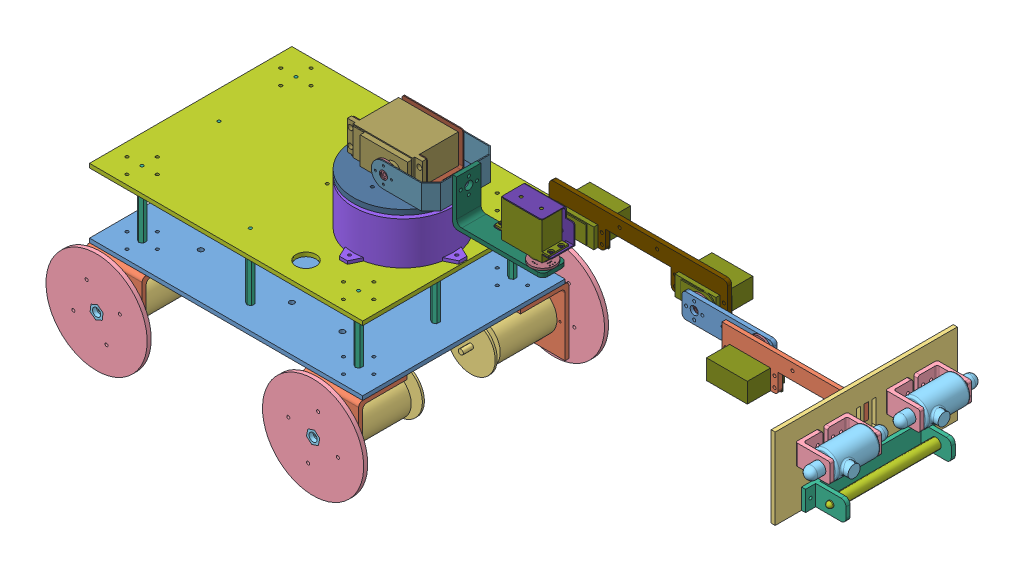
SolidWorks assembly robot_config4, configuration Default. Lengths in mm.
Overall size (760.42 282.73 242).
55 component instances, 25 part files, 137 mates.
Components (placement in the parent):
- base_odroid_down_fix-1: base_odroid_down_fix [Default] at (39.4639 122.941 229.7749) x (1 0 0) z (0 -1 0) size (270 200 4)
- link_motor_1_port-1: link_motor_1_port [Default] at (221.3654 112.3394 287.3354) x (0 0 -1) z (1 0 0) size (48 66 56)
- motor_dc_NISCA-1: motor_dc_NISCA [Default] at (244.2642 39.7289 313.6416) x (0 -1 0) z (0 0 -1) size (54 48 92)
- roda_shaft-1: roda_shaft [Default] at (185.8398 121.6563 330.6416) x (-0.980223 0.197896 0) z (0 0 1) size (100 100 4)
- shaft_adapter_5mm-1: shaft_adapter_5mm [Default] at (248.7954 72.9583 317.6416) x (0.980223 -0.197896 0) z (0 0 1) size (12 13.86 17)
- link_motor_1_port-2: link_motor_1_port [Default] at (221.3654 112.3394 139.9479) x (0 0 1) z (-1 0 0) size (48 66 56)
- motor_dc_NISCA-2: motor_dc_NISCA [Default] at (198.4666 39.7289 113.6416) x (0 -1 0) z (0 0 1) size (54 48 92)
- shaft_adapter_5mm-3: shaft_adapter_5mm [Default] at (238.0112 59.5291 109.6416) x (0.404857 -0.91438 0) z (0 0 -1) size (12 13.86 17)
- roda_shaft-2: roda_shaft [Default] at (222.1063 135.748 96.6416) x (0.589448 0.807807 0) z (0 0 -1) size (100 100 4)
- link_motor_1_port-5: link_motor_1_port [Default] at (7.3654 112.3394 287.3354) x (0 0 -1) z (1 0 0) size (48 66 56)
- motor_dc_NISCA-5: motor_dc_NISCA [Default] at (-15.5334 128.1531 313.6416) x (0 1 0) z (0 0 -1) size (54 48 92)
- roda_shaft-5: roda_shaft [Default] at (51.5287 56.8466 334.6416) x (0.393495 -0.919327 0) z (0 0 -1) size (100 100 4)
- shaft_adapter_5mm-6: shaft_adapter_5mm [Default] at (0.8367 112.7577 317.6416) x (-0.393495 0.919327 0) z (0 0 1) size (12 13.86 17)
- link_motor_1_port-6: link_motor_1_port [Default] at (7.3654 112.3394 139.9479) x (0 0 1) z (-1 0 0) size (48 66 56)
- motor_dc_NISCA-6: motor_dc_NISCA [Default] at (-15.5334 39.7289 113.6416) x (0 -1 0) z (0 0 1) size (54 48 92)
- roda_shaft-6: roda_shaft [Default] at (45.258 48.6046 96.6416) x (0.202799 -0.97922 0) z (0 0 -1) size (100 100 4)
- shaft_adapter_5mm-7: shaft_adapter_5mm [Default] at (36.6325 79.8838 109.6416) x (0.949429 -0.313981 0) z (0 0 -1) size (12 13.86 17)
- spacer_6cm-2: spacer_6cm [Default] at (221.7099 182.941 288.7798) x (0.5 0 -0.866025) z (0 -1 0) size (6 6.93 68)
- spacer_6cm-3: spacer_6cm [Default] at (114.7099 182.941 288.7798) x (0.5 0 -0.866025) z (0 -1 0) size (6 6.93 68)
- spacer_6cm-4: spacer_6cm [Default] at (7.7099 182.941 288.7798) x (0.5 0 -0.866025) z (0 -1 0) size (6 6.93 68)
- spacer_6cm-5: spacer_6cm [Default] at (221.7099 182.941 212.7798) x (0.5 0 -0.866025) z (0 -1 0) size (6 6.93 68)
- spacer_6cm-7: spacer_6cm [Default] at (7.7099 182.941 212.7798) x (0.5 0 -0.866025) z (0 -1 0) size (6 6.93 68)
- spacer_6cm-8: spacer_6cm [Default] at (221.7099 182.941 136.7798) x (0.5 0 -0.866025) z (0 -1 0) size (6 6.93 68)
- spacer_6cm-9: spacer_6cm [Default] at (114.7099 182.941 136.7798) x (0.5 0 -0.866025) z (0 -1 0) size (6 6.93 68)
- spacer_6cm-10: spacer_6cm [Default] at (7.7099 182.941 136.7798) x (0.5 0 -0.866025) z (0 -1 0) size (6 6.93 68)
- base_odroid_up_fix-1: base_odroid_up_fix [Default] at (189.2669 186.941 197.5083) x (-1 0 0) z (0 -1 0) size (270 200 4)
- base_arm-1: base_arm [Default] at (189.3654 194.0898 219.4289) x (0 0 1) z (-1 0 0) size (118.01 42 118.01)
- servo_hs422-1: servo_hs422 [Default] at (199.6524 210.6756 203.7356) x (0 0 1) z (-1 0 0) size (19.81 42.14 58.23)
- link1_arm-1: link1_arm [Default] at (162.7148 232.0663 213.6416) x (-1 0 0) z (0 1 0) size (98 98 12)
- bracket_servo_hs755-1: bracket_servo_hs755 [Default] at (226.3654 266.4802 252.854) x (0 0 1) z (-1 0 0) size (44 34 74)
- servo_hs755-1: servo_hs755 [Default] at (199.4663 211.9363 188.6416) x (0 -1 0) z (0 0 1) size (29 74 56.99)
- servo_horn_general-1: servo_horn_general [Default] at (158.1724 253.8913 247.6316) x (-1 0 0) z (0 0 -1) size (24 24 6)
- link2_ubracket-2: link2_ubracket [Default] at (243.847 269.0663 202.3382) x (0 0 -1) z (0 -1 0) size (66 59 24)
- link2_fix-2: link2_fix [Default] at (302.1273 265.014 203.2174) x (0 1 0) z (0 0 1) size (45.14 89 24)
- servo_horn_general-2: servo_horn_general [Default] at (282.1724 229.0663 212.0424) x (-1 0 0) z (0 1 0) size (24 24 6)
- servo_hs645-2: servo_hs645 [Default] at (371.772 273.4208 228.4385) x (1 0 0) z (0 -1 0) size (53.34 19.56 42.35)
- bracket_servo_645-2: bracket_servo_645 [Default] at (346.6974 227.1529 209.3754) x (0 -1 0) z (-1 0 0) size (34 24 57)
- servo_horn_general-3: servo_horn_general [Default] at (280.7737 260.864 201.2504) x (-0.965926 0.258819 0) z (0 0 -1) size (24 24 6)
- servo_hs645-3: servo_hs645 [Default] at (283.7908 238.6247 156.8959) x (-1 0 0) z (0 0 1) size (53.34 19.56 42.35)
- link4_fix-1: link4_fix [Default] at (524.8795 244.4473 185.4709) size (176.25 35 4)
- servo_hs645-4: servo_hs645 [Default] at (511.566 264.5589 156.8959) size (53.34 19.56 42.35)
- link5_fix-1: link5_fix [Default] at (491.6097 296.6345 201.2504) x (0 1 0) z (0 0 1) size (24 90 4)
- servo_horn_general-4: servo_horn_general [Default] at (421.9664 248.1628 201.2504) x (-1 0 0) z (0 0 -1) size (24 24 6)
- servo_horn_general-5: servo_horn_general [Default] at (581.3523 248.1628 205.2504) size (24 24 6)
- servo_hs645-5: servo_hs645 [Default] at (491.7528 264.5589 249.6049) x (-1 0 0) z (0 0 -1) size (53.34 19.56 42.35)
- link6_eff-1: link6_eff [Default] at (498.4393 244.4473 226.6809) x (-1 0 0) z (0 0 -1) size (140.63 35 4)
- base_link_effector_fix-2: base_link_effector_fix [Default] at (654.1404 277.9299 227.3815) x (0 0 -1) z (1 0 0) size (180 80 4)
- base_webcam_fix1-2: base_webcam_fix1 [Default] at (658.1404 278.3128 294.6809) x (0 0 -1) z (0 -1 0) size (23 34 20)
- base_webcam_fix1-3: base_webcam_fix1 [Default] at (658.1404 258.3128 243.6809) x (0 0 1) z (0 1 0) size (23 34 20)
- base_webcam_fix1-4: base_webcam_fix1 [Default] at (658.1404 278.3128 205.6809) x (0 0 -1) z (0 -1 0) size (23 34 20)
- base_webcam_fix1-5: base_webcam_fix1 [Default] at (658.1404 258.3128 154.6809) x (0 0 1) z (0 1 0) size (23 34 20)
- webcam_sturdy-3: webcam_sturdy [Default] at (682.1404 268.3128 243.37) x (0 0 -1) z (1 0 0) size (79 27 33.5)
- webcam_sturdy-4: webcam_sturdy [Default] at (682.1404 268.3128 154.37) x (0 0 -1) z (1 0 0) size (79 27 33.5)
- base_GM-1: base_GM [Default] at (666.3876 236.8128 184.9491) x (0 0 -1) z (0 -1 0) size (128 34 20)
- tabung_GM-1: tabung_GM [Default] at (725.7289 219.2089 174.6809) x (0.998525 0.054289 0) z (0 0 1) size (10 10 116)
Mates (geometry in assembly coordinates):
- Coincident1: coincident anti-aligned: plane of link_motor_1_port-1 through (193.3654 52.941 313.6416) normal (0 0 -1); plane of motor_dc_NISCA-1 through (221.3654 83.941 313.6416) normal (0 0 1)
- Concentric1: concentric aligned: cylinder of link_motor_1_port-1 through (221.3654 83.941 317.6416) axis (0 0 -1) radius 9.5; cylinder of motor_dc_NISCA-1 through (221.3654 83.941 317.6416) axis (0 0 -1) radius 9
- Concentric2: concentric anti-aligned: cylinder of link_motor_1_port-1 through (221.3654 106.941 317.6416) axis (0 0 -1) radius 1; cylinder of motor_dc_NISCA-1 through (221.3654 106.941 311.6416) axis (0 0 1) radius 1.5
- Coincident2: coincident anti-aligned: plane of motor_dc_NISCA-1 through (244.2642 39.7289 317.6416) normal (0 0 1); plane of shaft_adapter_5mm-1 through (221.3654 83.941 317.6416) normal (0 0 -1)
- Concentric4: concentric aligned: cylinder of motor_dc_NISCA-1 through (221.3654 83.941 330.6416) axis (0 0 -1) radius 2.5; cylinder of shaft_adapter_5mm-1 through (221.3654 83.941 330.6416) axis (0 0 -1) radius 2.5
- Coincident3: coincident anti-aligned: plane of roda_shaft-1 through (222.7365 90.7322 330.6416) normal (0.318728 -0.947846 0); plane of shaft_adapter_5mm-1 through (222.7365 90.7322 334.6416) normal (-0.318728 0.947846 0)
- Coincident4: coincident aligned: plane of roda_shaft-1 through (221.3654 83.941 334.6416) normal (0 0 1); plane of shaft_adapter_5mm-1 through (248.7954 72.9583 334.6416) normal (0 0 1)
- Coincident7: coincident anti-aligned: plane of roda_shaft-1 through (214.7985 81.7328 330.6416) normal (0.661495 0.74995 0); plane of shaft_adapter_5mm-1 through (214.7985 81.7328 334.6416) normal (-0.661495 -0.74995 0)
- Coincident8: coincident anti-aligned: plane of link_motor_1_port-2 through (249.3654 52.941 113.6416) normal (0 0 1); plane of motor_dc_NISCA-2 through (221.3654 83.941 113.6416) normal (0 0 -1)
- Concentric5: concentric aligned: cylinder of link_motor_1_port-2 through (221.3654 83.941 109.6416) axis (0 0 1) radius 9.5; cylinder of motor_dc_NISCA-2 through (221.3654 83.941 109.6416) axis (0 0 1) radius 9
- Concentric7: concentric anti-aligned: cylinder of link_motor_1_port-2 through (221.3654 106.941 109.6416) axis (0 0 1) radius 1; cylinder of motor_dc_NISCA-2 through (221.3654 106.941 115.6416) axis (0 0 -1) radius 1.5
- Coincident9: coincident anti-aligned: plane of base_odroid_down_fix-1 through (39.4639 118.941 229.7749) normal (0 -1 0); plane of link_motor_1_port-1 through (193.3654 118.941 269.6416) normal (0 1 0)
- Concentric8: concentric anti-aligned: cylinder of base_odroid_down_fix-1 through (206.3654 118.941 289.6416) axis (0 1 0) radius 1.5; cylinder of link_motor_1_port-1 through (206.3654 118.941 289.6416) axis (0 -1 0) radius 1.5
- Concentric9: concentric anti-aligned: cylinder of base_odroid_down_fix-1 through (236.3654 118.941 289.6416) axis (0 1 0) radius 1.5; cylinder of link_motor_1_port-1 through (236.3654 118.941 289.6416) axis (0 -1 0) radius 1.5
- Coincident11: coincident aligned: plane of shaft_adapter_5mm-3 through (238.0112 59.5291 92.6416) normal (0 0 -1); plane of roda_shaft-2 through (221.3654 83.941 92.6416) normal (0 0 -1)
- Coincident12: coincident anti-aligned: plane of shaft_adapter_5mm-3 through (220.627 77.0523 92.6416) normal (-0.589448 -0.807807 0); plane of roda_shaft-2 through (220.627 77.0523 96.6416) normal (0.589448 0.807807 0)
- Coincident13: coincident anti-aligned: plane of shaft_adapter_5mm-3 through (227.7004 86.746 92.6416) normal (0.994305 -0.106573 0); plane of roda_shaft-2 through (227.7004 86.746 96.6416) normal (-0.994305 0.106573 0)
- Coincident14: coincident anti-aligned: plane of motor_dc_NISCA-2 through (198.4666 39.7289 109.6416) normal (0 0 -1); plane of shaft_adapter_5mm-3 through (221.3654 83.941 109.6416) normal (0 0 1)
- Concentric10: concentric aligned: cylinder of motor_dc_NISCA-2 through (221.3654 83.941 96.6416) axis (0 0 1) radius 2.5; cylinder of shaft_adapter_5mm-3 through (221.3654 83.941 96.6416) axis (0 0 1) radius 2.5
- Coincident15: coincident anti-aligned: plane of base_odroid_down_fix-1 through (39.4639 118.941 229.7749) normal (0 -1 0); plane of link_motor_1_port-2 through (249.3654 118.941 157.6416) normal (0 1 0)
- Concentric11: concentric anti-aligned: cylinder of base_odroid_down_fix-1 through (206.3654 118.941 137.6416) axis (0 1 0) radius 1.5; cylinder of link_motor_1_port-2 through (206.3654 118.941 137.6416) axis (0 -1 0) radius 1.5
- Concentric12: concentric anti-aligned: cylinder of base_odroid_down_fix-1 through (236.3654 118.941 137.6416) axis (0 1 0) radius 1.5; cylinder of link_motor_1_port-2 through (236.3654 118.941 137.6416) axis (0 -1 0) radius 1.5
- Coincident16: coincident anti-aligned: plane of link_motor_1_port-5 through (-20.6346 52.941 313.6416) normal (0 0 -1); plane of motor_dc_NISCA-5 through (7.3654 83.941 313.6416) normal (0 0 1)
- Concentric13: concentric aligned: cylinder of link_motor_1_port-5 through (7.3654 83.941 317.6416) axis (0 0 -1) radius 9.5; cylinder of motor_dc_NISCA-5 through (7.3654 83.941 317.6416) axis (0 0 -1) radius 9
- Concentric14: concentric anti-aligned: cylinder of link_motor_1_port-5 through (7.3654 106.941 317.6416) axis (0 0 -1) radius 1; cylinder of motor_dc_NISCA-5 through (7.3654 106.941 311.6416) axis (0 0 1) radius 1.5
- Concentric16: concentric aligned: cylinder of motor_dc_NISCA-5 through (7.3654 83.941 330.6416) axis (0 0 -1) radius 2.5; cylinder of shaft_adapter_5mm-6 through (7.3654 83.941 330.6416) axis (0 0 -1) radius 2.5
- Coincident17: coincident anti-aligned: plane of motor_dc_NISCA-5 through (-15.5334 128.1531 317.6416) normal (0 0 1); plane of shaft_adapter_5mm-6 through (7.3654 83.941 317.6416) normal (0 0 -1)
- Coincident18: coincident anti-aligned: plane of roda_shaft-5 through (6.5417 77.062 334.6416) normal (0.599413 0.80044 0); plane of shaft_adapter_5mm-6 through (0.9961 81.2148 334.6416) normal (-0.599413 -0.80044 0)
- Coincident19: coincident aligned: plane of roda_shaft-5 through (7.3654 83.941 334.6416) normal (0 0 1); plane of shaft_adapter_5mm-6 through (0.8367 112.7577 334.6416) normal (0 0 1)
- Coincident20: coincident anti-aligned: plane of roda_shaft-5 through (1.8198 88.0939 334.6416) normal (0.393495 -0.919327 0); plane of shaft_adapter_5mm-6 through (8.1891 90.8201 334.6416) normal (-0.393495 0.919327 0)
- Coincident21: coincident anti-aligned: plane of base_odroid_down_fix-1 through (39.4639 118.941 229.7749) normal (0 -1 0); plane of link_motor_1_port-5 through (-20.6346 118.941 269.6416) normal (0 1 0)
- Concentric17: concentric anti-aligned: cylinder of base_odroid_down_fix-1 through (-7.6346 118.941 289.6416) axis (0 1 0) radius 1.5; cylinder of link_motor_1_port-5 through (-7.6346 118.941 289.6416) axis (0 -1 0) radius 1.5
- Concentric18: concentric anti-aligned: cylinder of base_odroid_down_fix-1 through (22.3654 118.941 289.6416) axis (0 1 0) radius 1.5; cylinder of link_motor_1_port-5 through (22.3654 118.941 289.6416) axis (0 -1 0) radius 1.5
- Coincident22: coincident anti-aligned: plane of link_motor_1_port-6 through (35.3654 52.941 113.6416) normal (0 0 1); plane of motor_dc_NISCA-6 through (7.3654 83.941 113.6416) normal (0 0 -1)
- Concentric19: concentric aligned: cylinder of link_motor_1_port-6 through (7.3654 83.941 109.6416) axis (0 0 1) radius 9.5; cylinder of motor_dc_NISCA-6 through (7.3654 83.941 109.6416) axis (0 0 1) radius 9
- Concentric20: concentric anti-aligned: cylinder of link_motor_1_port-6 through (7.3654 106.941 109.6416) axis (0 0 1) radius 1; cylinder of motor_dc_NISCA-6 through (7.3654 106.941 115.6416) axis (0 0 -1) radius 1.5
- Concentric21: concentric aligned: cylinder of motor_dc_NISCA-6 through (7.3654 83.941 96.6416) axis (0 0 1) radius 2.5; cylinder of shaft_adapter_5mm-7 through (7.3654 83.941 96.6416) axis (0 0 1) radius 2.5
- Coincident23: coincident anti-aligned: plane of motor_dc_NISCA-6 through (-15.5334 39.7289 109.6416) normal (0 0 -1); plane of shaft_adapter_5mm-7 through (7.3654 83.941 109.6416) normal (0 0 1)
- Coincident24: coincident aligned: plane of roda_shaft-6 through (7.3654 83.941 92.6416) normal (0 0 -1); plane of shaft_adapter_5mm-7 through (36.6325 79.8838 92.6416) normal (0 0 -1)
- Coincident25: coincident anti-aligned: plane of roda_shaft-6 through (2.7565 89.1138 96.6416) normal (0.202799 -0.97922 0); plane of shaft_adapter_5mm-7 through (2.7565 89.1138 92.6416) normal (-0.202799 0.97922 0)
- Coincident26: coincident anti-aligned: plane of roda_shaft-6 through (5.1901 77.3632 96.6416) normal (0.74663 0.665239 0); plane of shaft_adapter_5mm-7 through (5.1901 77.3632 92.6416) normal (-0.74663 -0.665239 0)
- Coincident27: coincident anti-aligned: plane of base_odroid_down_fix-1 through (39.4639 118.941 229.7749) normal (0 -1 0); plane of link_motor_1_port-6 through (35.3654 118.941 157.6416) normal (0 1 0)
- Concentric22: concentric anti-aligned: cylinder of base_odroid_down_fix-1 through (-7.6346 118.941 137.6416) axis (0 1 0) radius 1.5; cylinder of link_motor_1_port-6 through (-7.6346 118.941 137.6416) axis (0 -1 0) radius 1.5
- Concentric23: concentric anti-aligned: cylinder of base_odroid_down_fix-1 through (22.3654 118.941 137.6416) axis (0 1 0) radius 1.5; cylinder of link_motor_1_port-6 through (22.3654 118.941 137.6416) axis (0 -1 0) radius 1.5
- Concentric24: concentric aligned: cylinder of base_odroid_down_fix-1 through (221.3654 118.941 289.6416) axis (0 1 0) radius 1.5; cylinder of spacer_6cm-2 through (221.3654 118.941 289.6416) axis (0 1 0) radius 1.5
- Coincident28: coincident anti-aligned: plane of base_odroid_down_fix-1 through (39.4639 122.941 229.7749) normal (0 1 0); plane of spacer_6cm-2 through (221.7099 122.941 288.7798) normal (0 -1 0)
- Parallel2: parallel aligned: plane of base_odroid_down_fix-1 through (249.3654 118.941 229.7749) normal (1 0 0); plane of spacer_6cm-2 through (224.3654 122.941 287.9096) normal (1 0 0)
- Concentric25: concentric anti-aligned: cylinder of spacer_6cm-2 through (221.3654 186.941 289.6416) axis (0 -1 0) radius 1.5; cylinder of base_odroid_up_fix-1 through (221.3654 182.941 289.6416) axis (0 1 0) radius 1.5
- Concentric26: concentric anti-aligned: cylinder of spacer_6cm-7 through (7.3654 186.941 213.6416) axis (0 -1 0) radius 1.5; cylinder of base_odroid_up_fix-1 through (7.3654 182.941 213.6416) axis (0 1 0) radius 1.5
- Coincident29: coincident anti-aligned: plane of spacer_6cm-2 through (221.7099 182.941 288.7798) normal (0 1 0); plane of base_odroid_up_fix-1 through (189.2669 182.941 197.5083) normal (0 -1 0)
- Coincident31: coincident anti-aligned: plane of base_arm-1 through (189.3654 225.941 213.6416) normal (0 -1 0); plane of servo_hs422-1 through (199.6524 225.941 203.7356) normal (0 1 0)
- Parallel3: parallel aligned: plane of base_odroid_up_fix-1 through (249.3654 182.941 197.5083) normal (1 0 0); plane of servo_hs422-1 through (219.5914 210.6756 223.5476) normal (1 0 0)
- Coincident33: coincident anti-aligned: plane of base_odroid_up_fix-1 through (189.2669 186.941 197.5083) normal (0 1 0); plane of base_arm-1 through (189.3654 186.941 259.6416) normal (0 -1 0)
- Concentric28: concentric anti-aligned: cylinder of base_odroid_up_fix-1 through (242.3654 182.941 213.6416) axis (0 1 0) radius 1.5; cylinder of base_arm-1 through (242.3654 189.941 213.6416) axis (0 -1 0) radius 1.5
- Concentric29: concentric anti-aligned: cylinder of base_odroid_up_fix-1 through (189.3654 182.941 160.6416) axis (0 1 0) radius 1.5; cylinder of base_arm-1 through (189.3654 189.941 160.6416) axis (0 -1 0) radius 1.5
- Parallel5: parallel aligned: plane of base_odroid_up_fix-1 through (189.2669 182.941 113.6416) normal (0 0 -1); plane of servo_hs422-1 through (199.6524 210.6756 203.7356) normal (0 0 -1)
- Concentric30: concentric aligned: cylinder of base_arm-1 through (189.3654 225.941 213.6416) axis (0 1 0) radius 5.4623; cylinder of servo_hs422-1 through (189.3654 202.0734 213.6416) axis (0 1 0) radius 6.4897
- Concentric31: concentric aligned: cylinder of servo_hs422-1 through (189.3654 212.8107 213.6416) axis (0 1 0) radius 2.8131; cylinder of link1_arm-1 through (189.3654 228.0663 213.6416) axis (0 1 0) radius 3
- Coincident36: coincident anti-aligned: plane of servo_hs422-1 through (199.6524 232.0663 223.5476) normal (0 1 0); plane of link1_arm-1 through (189.3654 232.0663 213.6416) normal (0 -1 0)
- Concentric32: concentric aligned: cylinder of link1_arm-1 through (189.3654 240.0663 213.6416) axis (0 -1 0) radius 4; cylinder of bracket_servo_hs755-1 through (189.3654 238.0663 213.6416) axis (0 -1 0) radius 4
- Coincident38: coincident anti-aligned: plane of link1_arm-1 through (189.3654 237.0663 213.6416) normal (0 1 0); plane of bracket_servo_hs755-1 through (149.5696 237.0663 187.4635) normal (0 -1 0)
- Concentric33: concentric anti-aligned: cylinder of link1_arm-1 through (181.4049 232.0663 214.4359) axis (0 1 0) radius 1.5; cylinder of bracket_servo_hs755-1 through (181.4049 238.0663 214.4359) axis (0 -1 0) radius 1.5
- Coincident40: coincident anti-aligned: plane of bracket_servo_hs755-1 through (153.9382 237.0663 231.2461) normal (0.099287 0 0.995059); plane of servo_hs755-1 through (200.8064 211.9363 226.5695) normal (-0.099287 0 -0.995059)
- Concentric36: concentric aligned: cylinder of bracket_servo_hs755-1 through (156.8241 248.5663 229.9531) axis (0.099287 0 0.995059) radius 1.5; cylinder of servo_hs755-1 through (156.9234 248.5663 230.9482) axis (0.099287 0 0.995059) radius 2.5
- Concentric37: concentric aligned: cylinder of bracket_servo_hs755-1 through (224.4881 264.5663 223.2016) axis (0.099287 0 0.995059) radius 1.5; cylinder of servo_hs755-1 through (224.5874 264.5663 224.1967) axis (0.099287 0 0.995059) radius 2.5
- Concentric39: concentric anti-aligned: cylinder of servo_hs755-1 through (207.965 257.0663 243.9346) axis (-0.099287 0 -0.995059) radius 3; cylinder of servo_horn_general-1 through (207.6671 257.0663 240.9494) axis (0.099287 0 0.995059) radius 3
- Coincident41: coincident anti-aligned: plane of servo_hs755-1 through (207.965 257.0663 243.9346) normal (0.099287 0 0.995059); plane of servo_horn_general-1 through (207.965 257.0663 243.9346) normal (-0.099287 0 -0.995059)
- Concentric40: concentric anti-aligned: cylinder of servo_horn_general-1 through (208.2629 257.0663 246.9198) axis (-0.099287 0 -0.995059) radius 4; cylinder of link2_ubracket-2 through (208.1636 257.0663 245.9247) axis (0.099287 0 0.995059) radius 4
- Coincident42: coincident anti-aligned: plane of servo_horn_general-1 through (208.1636 257.0663 245.9247) normal (0.099287 0 0.995059); plane of link2_ubracket-2 through (245.1515 245.0663 242.2341) normal (-0.099287 0 -0.995059)
- Concentric41: concentric aligned: cylinder of servo_horn_general-1 through (207.965 265.0663 243.9346) axis (0.099287 0 0.995059) radius 0.5; cylinder of link2_ubracket-2 through (208.1636 265.0663 245.9247) axis (0.099287 0 0.995059) radius 1
- Coincident46: coincident anti-aligned: plane of link2_ubracket-2 through (254.0959 245.0663 232.8856) normal (0.995059 0 -0.099287); plane of link2_fix-2 through (252.9045 265.014 220.9449) normal (-0.995059 0 0.099287)
- Concentric45: concentric anti-aligned: cylinder of link2_ubracket-2 through (250.718 257.0663 209.1035) axis (0.995059 0 -0.099287) radius 4; cylinder of link2_fix-2 through (255.6933 257.0663 208.607) axis (-0.995059 0 0.099287) radius 4
- Concentric46: concentric anti-aligned: cylinder of link2_ubracket-2 through (249.9237 257.0663 201.143) axis (0.995059 0 -0.099287) radius 1; cylinder of link2_fix-2 through (254.899 257.0663 200.6466) axis (-0.995059 0 0.099287) radius 1.5
- Coincident47: coincident anti-aligned: plane of servo_horn_general-2 through (328.3325 231.0663 201.3591) normal (0 1 0); plane of servo_hs645-2 through (328.3325 231.0663 201.3591) normal (0 -1 0)
- Concentric48: concentric anti-aligned: cylinder of servo_horn_general-2 through (328.3325 234.0663 201.3591) axis (0 -1 0) radius 3; cylinder of servo_hs645-2 through (328.3325 231.0663 201.3591) axis (0 1 0) radius 2.9972
- Coincident48: coincident anti-aligned: plane of link2_fix-2 through (302.9181 229.0663 215.9545) normal (0 1 0); plane of servo_horn_general-2 through (328.3325 229.0663 201.3591) normal (0 -1 0)
- Concentric49: concentric anti-aligned: cylinder of link2_fix-2 through (328.3325 229.0663 201.3591) axis (0 -1 0) radius 4; cylinder of servo_horn_general-2 through (328.3325 228.0663 201.3591) axis (0 1 0) radius 4
- Concentric50: concentric aligned: cylinder of link2_fix-2 through (327.5383 229.0663 193.3986) axis (0 -1 0) radius 1.5; cylinder of servo_horn_general-2 through (327.5383 231.0663 193.3986) axis (0 -1 0) radius 0.5
- Coincident50: coincident anti-aligned: plane of servo_hs645-2 through (372.3398 244.8458 210.2547) normal (0 -1 0); plane of bracket_servo_645-2 through (288.0706 244.8458 192.345) normal (0 1 0)
- Concentric51: concentric aligned: cylinder of servo_hs645-2 through (342.2576 248.0208 205.3301) axis (0 -1 0) radius 2.5019; cylinder of bracket_servo_645-2 through (342.2576 246.3858 205.3301) axis (0 -1 0) radius 1.5
- Concentric52: concentric aligned: cylinder of servo_hs645-2 through (294.2361 248.0208 210.1217) axis (0 -1 0) radius 2.5019; cylinder of bracket_servo_645-2 through (294.2361 246.3858 210.1217) axis (0 -1 0) radius 1.5
- Concentric53: concentric aligned: cylinder of bracket_servo_645-2 through (324.8878 251.8458 188.6714) axis (-0.099287 0 -0.995059) radius 4; cylinder of servo_horn_general-3 through (324.8878 251.8458 188.6714) axis (-0.099287 0 -0.995059) radius 4
- Coincident51: coincident anti-aligned: plane of bracket_servo_645-2 through (287.9713 273.8458 191.35) normal (-0.099287 0 -0.995059); plane of servo_horn_general-3 through (324.7885 251.8458 187.6763) normal (0.099287 0 0.995059)
- Concentric54: concentric anti-aligned: cylinder of bracket_servo_645-2 through (324.8878 259.8458 188.6714) axis (-0.099287 0 -0.995059) radius 1.5; cylinder of servo_horn_general-3 through (324.5899 259.8458 185.6862) axis (0.099287 0 0.995059) radius 0.5
- Coincident52: coincident anti-aligned: plane of servo_horn_general-3 through (324.5899 251.8458 185.6862) normal (-0.099287 0 -0.995059); plane of servo_hs645-3 through (324.5899 251.8458 185.6862) normal (0.099287 0 0.995059)
- Concentric55: concentric anti-aligned: cylinder of servo_horn_general-3 through (324.2921 251.8458 182.701) axis (0.099287 0 0.995059) radius 3; cylinder of servo_hs645-3 through (324.5899 251.8458 185.6862) axis (-0.099287 0 -0.995059) radius 2.9972
- Concentric61: concentric anti-aligned: cylinder of servo_hs645-4 through (465.8505 251.3378 171.5912) axis (-0.099287 0 -0.995059) radius 2.9972; cylinder of servo_horn_general-4 through (465.5526 251.3378 168.606) axis (0.099287 0 0.995059) radius 3
- Coincident56: coincident anti-aligned: plane of servo_hs645-4 through (465.8505 251.3378 171.5912) normal (0.099287 0 0.995059); plane of servo_horn_general-4 through (465.8505 251.3378 171.5912) normal (-0.099287 0 -0.995059)
- Coincident57: coincident anti-aligned: plane of link5_fix-1 through (488.886 296.6345 171.3027) normal (-0.099287 0 -0.995059); plane of servo_horn_general-4 through (466.0491 251.3378 173.5813) normal (0.099287 0 0.995059)
- Concentric62: concentric anti-aligned: cylinder of link5_fix-1 through (466.0491 251.3378 173.5813) axis (0.099287 0 0.995059) radius 4; cylinder of servo_horn_general-4 through (466.1483 251.3378 174.5764) axis (-0.099287 0 -0.995059) radius 4
- Concentric63: concentric aligned: cylinder of link5_fix-1 through (466.0491 259.3378 173.5813) axis (0.099287 0 0.995059) radius 1.5; cylinder of servo_horn_general-4 through (465.8505 259.3378 171.5912) axis (0.099287 0 0.995059) radius 0.5
- Concentric64: concentric anti-aligned: cylinder of servo_horn_general-5 through (532.6165 251.3378 175.9839) axis (-0.099287 0 -0.995059) radius 3; cylinder of servo_hs645-5 through (532.3187 251.3378 172.9987) axis (0.099287 0 0.995059) radius 2.9972
- Coincident58: coincident anti-aligned: plane of servo_horn_general-5 through (532.3187 251.3378 172.9987) normal (0.099287 0 0.995059); plane of servo_hs645-5 through (532.3187 251.3378 172.9987) normal (-0.099287 0 -0.995059)
- Coincident59: coincident anti-aligned: plane of link5_fix-1 through (489.2831 296.6345 175.2829) normal (0.099287 0 0.995059); plane of servo_horn_general-5 through (532.1201 251.3378 171.0086) normal (-0.099287 0 -0.995059)
- Concentric65: concentric aligned: cylinder of link5_fix-1 through (531.7229 251.3378 167.0284) axis (0.099287 0 0.995059) radius 4; cylinder of servo_horn_general-5 through (532.0208 251.3378 170.0136) axis (0.099287 0 0.995059) radius 4
- Concentric66: concentric anti-aligned: cylinder of link5_fix-1 through (531.7229 243.3378 167.0284) axis (0.099287 0 0.995059) radius 1.5; cylinder of servo_horn_general-5 through (532.3187 243.3378 172.9987) axis (-0.099287 0 -0.995059) radius 0.5
- Coincident60: coincident anti-aligned: plane of servo_hs645-5 through (491.1561 264.5589 192.6131) normal (0.099287 0 0.995059); plane of link6_eff-1 through (497.8096 244.4473 191.9492) normal (-0.099287 0 -0.995059)
- Concentric67: concentric aligned: cylinder of servo_hs645-5 through (520.6065 246.5118 191.2061) axis (-0.099287 0 -0.995059) radius 2.5019; cylinder of link6_eff-1 through (520.8524 246.5118 193.6698) axis (-0.099287 0 -0.995059) radius 1.5
- Concentric68: concentric aligned: cylinder of servo_hs645-5 through (568.6281 246.5118 186.4145) axis (-0.099287 0 -0.995059) radius 2.5019; cylinder of link6_eff-1 through (568.8739 246.5118 188.8782) axis (-0.099287 0 -0.995059) radius 1.5
- Coincident61: coincident aligned: plane of link6_eff-1 through (656.7216 244.4473 176.0929) normal (0.995059 0 -0.099287); plane of base_link_effector_fix-2 through (657.1883 277.9299 180.7703) normal (0.995059 0 -0.099287)
- Coincident62: coincident anti-aligned: plane of link6_eff-1 through (497.8096 244.4473 191.9492) normal (-0.099287 0 -0.995059); plane of base_link_effector_fix-2 through (652.7413 276.8128 176.4901) normal (0.099287 0 0.995059)
- Coincident63: coincident anti-aligned: plane of link6_eff-1 through (497.8096 276.8128 191.9492) normal (0 1 0); plane of base_link_effector_fix-2 through (653.1385 276.8128 180.4703) normal (0 -1 0)
- Coincident72: coincident anti-aligned: plane of base_link_effector_fix-2 through (657.1883 277.9299 180.7703) normal (0.995059 0 -0.099287); plane of base_webcam_fix1-2 through (663.8702 258.3128 247.7372) normal (-0.995059 0 0.099287)
- Concentric71: concentric anti-aligned: cylinder of base_link_effector_fix-2 through (662.0831 268.3128 229.8261) axis (-0.995059 0 0.099287) radius 1.5; cylinder of base_webcam_fix1-2 through (662.0831 268.3128 229.8261) axis (0.995059 0 -0.099287) radius 1.5
- Concentric72: concentric anti-aligned: cylinder of base_link_effector_fix-2 through (662.8774 268.3128 237.7866) axis (-0.995059 0 0.099287) radius 1.5; cylinder of base_webcam_fix1-2 through (662.8774 268.3128 237.7866) axis (0.995059 0 -0.099287) radius 1.5
- Coincident73: coincident anti-aligned: plane of base_link_effector_fix-2 through (657.1883 277.9299 180.7703) normal (0.995059 0 -0.099287); plane of base_webcam_fix1-3 through (658.8066 278.3128 196.9892) normal (-0.995059 0 0.099287)
- Concentric73: concentric anti-aligned: cylinder of base_link_effector_fix-2 through (659.7995 268.3128 206.9397) axis (-0.995059 0 0.099287) radius 1.5; cylinder of base_webcam_fix1-3 through (659.7995 268.3128 206.9397) axis (0.995059 0 -0.099287) radius 1.5
- Concentric74: concentric anti-aligned: cylinder of base_link_effector_fix-2 through (660.5938 268.3128 214.9002) axis (-0.995059 0 0.099287) radius 1.5; cylinder of base_webcam_fix1-3 through (660.5938 268.3128 214.9002) axis (0.995059 0 -0.099287) radius 1.5
- Coincident74: coincident anti-aligned: plane of base_link_effector_fix-2 through (657.1883 277.9299 180.7703) normal (0.995059 0 -0.099287); plane of base_webcam_fix1-4 through (655.0337 258.3128 159.1769) normal (-0.995059 0 0.099287)
- Concentric75: concentric anti-aligned: cylinder of base_link_effector_fix-2 through (653.2465 268.3128 141.2659) axis (-0.995059 0 0.099287) radius 1.5; cylinder of base_webcam_fix1-4 through (653.2465 268.3128 141.2659) axis (0.995059 0 -0.099287) radius 1.5
- Concentric76: concentric anti-aligned: cylinder of base_link_effector_fix-2 through (654.0408 268.3128 149.2263) axis (-0.995059 0 0.099287) radius 1.5; cylinder of base_webcam_fix1-4 through (654.0408 268.3128 149.2263) axis (0.995059 0 -0.099287) radius 1.5
- Coincident75: coincident anti-aligned: plane of base_link_effector_fix-2 through (657.1883 277.9299 180.7703) normal (0.995059 0 -0.099287); plane of base_webcam_fix1-5 through (649.97 278.3128 108.4289) normal (-0.995059 0 0.099287)
- Concentric77: concentric anti-aligned: cylinder of base_link_effector_fix-2 through (651.7572 268.3128 126.34) axis (-0.995059 0 0.099287) radius 1.5; cylinder of base_webcam_fix1-5 through (651.7572 268.3128 126.34) axis (0.995059 0 -0.099287) radius 1.5
- Concentric78: concentric anti-aligned: cylinder of base_link_effector_fix-2 through (650.9629 268.3128 118.3795) axis (-0.995059 0 0.099287) radius 1.5; cylinder of base_webcam_fix1-5 through (650.9629 268.3128 118.3795) axis (0.995059 0 -0.099287) radius 1.5
- Concentric79: concentric anti-aligned: cylinder of base_webcam_fix1-2 through (687.3545 268.3128 241.374) axis (0.099287 0 0.995059) radius 6; cylinder of webcam_sturdy-3 through (689.1417 268.3128 259.2851) axis (-0.099287 0 -0.995059) radius 6
- Coincident78: coincident anti-aligned: plane of base_webcam_fix1-3 through (663.184 278.3128 200.5722) normal (0.099287 0 0.995059); plane of webcam_sturdy-3 through (683.0852 268.3128 198.5865) normal (-0.099287 0 -0.995059)
- Parallel8: parallel aligned: plane of base_link_effector_fix-2 through (657.1883 277.9299 180.7703) normal (0.995059 0 -0.099287); plane of webcam_sturdy-3 through (706.2628 268.3128 229.4377) normal (0.995059 0 -0.099287)
- Concentric80: concentric anti-aligned: cylinder of base_webcam_fix1-4 through (678.518 268.3128 152.8138) axis (0.099287 0 0.995059) radius 6; cylinder of webcam_sturdy-4 through (680.3051 268.3128 170.7249) axis (-0.099287 0 -0.995059) radius 6
- Coincident80: coincident anti-aligned: plane of base_webcam_fix1-5 through (654.3474 278.3128 112.012) normal (0.099287 0 0.995059); plane of webcam_sturdy-4 through (674.2486 268.3128 110.0263) normal (-0.099287 0 -0.995059)
- Parallel9: parallel aligned: plane of base_link_effector_fix-2 through (657.1883 277.9299 180.7703) normal (0.995059 0 -0.099287); plane of webcam_sturdy-4 through (697.4263 268.3128 140.8775) normal (0.995059 0 -0.099287)
- Coincident82: coincident anti-aligned: plane of base_link_effector_fix-2 through (657.1883 277.9299 180.7703) normal (0.995059 0 -0.099287); plane of base_GM-1 through (662.2817 216.8128 231.8162) normal (-0.995059 0 0.099287)
- Concentric81: concentric anti-aligned: cylinder of base_link_effector_fix-2 through (651.0622 226.8128 119.3746) axis (-0.995059 0 0.099287) radius 1.5; cylinder of base_GM-1 through (651.0622 226.8128 119.3746) axis (0.995059 0 -0.099287) radius 1.5
- Concentric82: concentric anti-aligned: cylinder of base_link_effector_fix-2 through (662.7781 226.8128 236.7915) axis (-0.995059 0 0.099287) radius 1.5; cylinder of base_GM-1 through (662.7781 226.8128 236.7915) axis (0.995059 0 -0.099287) radius 1.5
- Concentric83: concentric anti-aligned: cylinder of base_GM-1 through (670.8619 226.8128 126.4436) axis (-0.099287 0 -0.995059) radius 3; cylinder of tabung_GM-1 through (670.0676 226.8128 118.4832) axis (0.099287 0 0.995059) radius 3
- Coincident83: coincident anti-aligned: plane of base_GM-1 through (695.7165 216.8128 224.4602) normal (-0.099287 0 -0.995059); plane of tabung_GM-1 through (680.7906 226.8128 225.9495) normal (0.099287 0 0.995059)
- Coincident85: coincident anti-aligned: plane of link4_fix-1 through (520.4247 244.4473 152.2979) normal (-0.099287 0 -0.995059); plane of servo_hs645-4 through (507.177 264.5589 153.6197) normal (0.099287 0 0.995059)
- Concentric86: concentric aligned: cylinder of link4_fix-1 through (477.8778 246.5118 156.5432) axis (0.099287 0 0.995059) radius 1.5; cylinder of servo_hs645-4 through (477.5626 246.5118 153.3839) axis (0.099287 0 0.995059) radius 2.5019
- Concentric87: concentric aligned: cylinder of link4_fix-1 through (429.8563 256.6718 161.3348) axis (0.099287 0 0.995059) radius 1.5; cylinder of servo_hs645-4 through (429.5411 256.6718 158.1755) axis (0.099287 0 0.995059) radius 2.5019
- Coincident86: coincident anti-aligned: plane of servo_hs645-3 through (280.5272 238.6247 176.2349) normal (0.099287 0 0.995059); plane of link4_fix-1 through (520.4247 244.4473 152.2979) normal (-0.099287 0 -0.995059)
- Concentric88: concentric aligned: cylinder of servo_hs645-3 through (309.5111 246.5118 170.1521) axis (0.099287 0 0.995059) radius 2.5019; cylinder of link4_fix-1 through (309.8263 246.5118 173.3114) axis (0.099287 0 0.995059) radius 1.5
- Concentric89: concentric aligned: cylinder of servo_hs645-3 through (357.5326 246.5118 165.3605) axis (0.099287 0 0.995059) radius 2.5019; cylinder of link4_fix-1 through (357.8479 246.5118 168.5198) axis (0.099287 0 0.995059) radius 1.5
- LimitAngle1: limit planar angle = 1.570796 rad anti-aligned: plane of servo_hs755-1 through (199.4663 211.9363 188.6416) normal (0 0 -1); plane of base_odroid_up_fix-1 through (249.3654 182.941 197.5083) normal (1 0 0)
- LimitAngle2: limit planar angle = 0 rad aligned: plane of servo_hs755-1 through (218.8654 271.0663 231.6416) normal (0 1 0); plane of link2_ubracket-2 through (243.847 269.0663 202.3382) normal (0 1 0)
- LimitAngle3: limit planar angle = 1.570796 rad anti-aligned: plane of servo_hs645-2 through (338.3904 246.4968 225.2504) normal (1 0 0); plane of link2_fix-2 through (302.1273 265.014 227.2174) normal (0 0 1)
- LimitAngle4: limit planar angle = 1.570796 rad anti-aligned: plane of link4_fix-1 through (524.8795 276.8128 189.4709) normal (0 1 0); plane of servo_hs645-2 through (298.0044 246.4968 225.2504) normal (-1 0 0)
- LimitAngle5: limit planar angle = 1.570796 rad anti-aligned: plane of link4_fix-1 through (485.8044 244.4473 189.4709) normal (1 0 0); plane of link5_fix-1 through (456.6594 239.3378 205.2504) normal (0 -1 0)
- LimitAngle6: limit planar angle = 1.570796 rad anti-aligned: plane of link5_fix-1 through (546.6594 239.3378 205.2504) normal (1 0 0); plane of servo_hs645-5 through (565.5204 261.3708 222.6809) normal (0 1 0)
